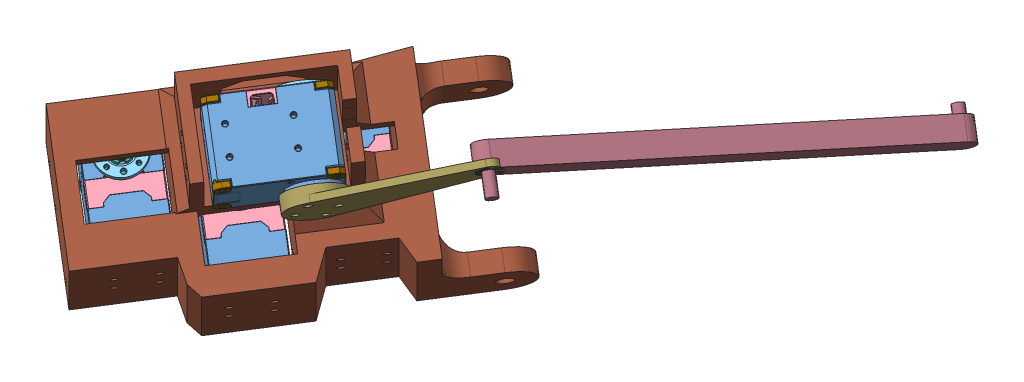
SolidWorks assembly Assemblage Avant bras, configuration Default. Lengths in mm.
Overall size (268.98 138.02 285.22).
110 component instances, 13 part files, 23 mates.
Components (placement in the parent):
- XL-430_new-1: XL-430_new [Default] at (80.3651 -130.963 113.251) x (0.630097 0.085354 -0.771811) z (-0.461076 -0.758631 -0.460313) size (28.5 46.5 40.9)
  - XL-430_new.stp-1: XL-430_new.stp [Default] at origin size (28.5 46.5 40.9)
    - DC11_A01_DUMMY.stp-1: DC11_A01_DUMMY.stp [Default] at origin size (28.5 46.5 37.9)
    - DX124_SCREW-COVER.stp-1: DX124_SCREW-COVER.stp [Default] at (11.75 0 13.7) x (-1 0 0) z (0 1 0) size (3.5 30.65 3.5)
    - B3B-EH.stp-1: B3B-EH.stp [Default] at (10.15 -14.1 -3.8) x (0 -1 0) z (1 0 0) size (10 9.2 3.8)
    - B3B-EH.stp-2: B3B-EH.stp [Default] at (-10.15 -14.1 -3.8) x (0 1 0) z (-1 0 0) size (10 9.2 3.8)
    - DC11_A01_CASE_CVR_DUMMY.stp-1: DC11_A01_CASE_CVR_DUMMY.stp [Default] at origin size (28.3 17.62 8.31)
    - DC11_A01_IDLER_DUMMY.stp-1: DC11_A01_IDLER_DUMMY.stp [Default] at (0 0 -19) x (1 0 0) z (0 1 0) size (20.5 3.5 20.5)
    - DC11_A01_IDLER_CAP_DUMMY.stp-1: DC11_A01_IDLER_CAP_DUMMY.stp [Default] at (0 0 -18.8) x (1 0 0) z (0 -1 0) size (10.1 5.2 10.37)
    - DC11_A01_IDLER_SCREW.stp-1: DC11_A01_IDLER_SCREW.stp [Default] at (0 0 -15.1) x (-1 0 0) z (0 -1 0) size (5 5.01 5)
    - FHS_M2_5X10.stp-1: FHS_M2_5X10.stp [Default] at (11 8 12.95) x (-1 0 0) z (0 1 0) size (5 10.01 5)
    - FHS_M2_5X10.stp-2: FHS_M2_5X10.stp [Default] at (-11 8 12.95) x (-1 0 0) z (0 1 0) size (5 10.01 5)
    - FHS_M2_5X10.stp-3: FHS_M2_5X10.stp [Default] at (-11 -32 12.95) x (-1 0 0) z (0 1 0) size (5 10.01 5)
    - FHS_M2_5X10.stp-4: FHS_M2_5X10.stp [Default] at (11 -32 12.95) x (-1 0 0) z (0 1 0) size (5 10.01 5)
    - FHS_M2_5X10.stp-5: FHS_M2_5X10.stp [Default] at (-11 8 -12.95) x (1 0 0) z (0 1 0) size (5 10.01 5)
    - FHS_M2_5X10.stp-6: FHS_M2_5X10.stp [Default] at (11 8 -12.95) x (1 0 0) z (0 1 0) size (5 10.01 5)
    - FHS_M2_5X10.stp-7: FHS_M2_5X10.stp [Default] at (-11 -32 -12.95) x (1 0 0) z (0 1 0) size (5 10.01 5)
    - FHS_M2_5X10.stp-8: FHS_M2_5X10.stp [Default] at (11 -32 -12.95) x (1 0 0) z (0 1 0) size (5 10.01 5)
    - DC11_A01_SPACER_DUMMY.stp-1: DC11_A01_SPACER_DUMMY.stp [Default] at (11 8 14.2) x (-1 0 0) z (0 0 1) size (6.5 6.5 3.9)
    - DC11_A01_SPACER_DUMMY.stp-2: DC11_A01_SPACER_DUMMY.stp [Default] at (-11 8 14.2) x (0 -1 0) z (0 0 1) size (6.5 6.5 3.9)
    - DC11_A01_SPACER_DUMMY.stp-3: DC11_A01_SPACER_DUMMY.stp [Default] at (-11 -32 14.2) x (-1 0 0) z (0 0 1) size (6.5 6.5 3.9)
    - DC11_A01_SPACER_DUMMY.stp-4: DC11_A01_SPACER_DUMMY.stp [Default] at (11 -32 14.2) x (0 1 0) z (0 0 1) size (6.5 6.5 3.9)
    - DC11_A01_SPACER_DUMMY.stp-5: DC11_A01_SPACER_DUMMY.stp [Default] at (11 8 -14.2) x (0 -1 0) z (0 0 -1) size (6.5 6.5 3.9)
    - DC11_A01_SPACER_DUMMY.stp-6: DC11_A01_SPACER_DUMMY.stp [Default] at (-11 8 -14.2) x (1 0 0) z (0 0 -1) size (6.5 6.5 3.9)
    - DC11_A01_SPACER_DUMMY.stp-7: DC11_A01_SPACER_DUMMY.stp [Default] at (11 -32 -14.2) x (-1 0 0) z (0 0 -1) size (6.5 6.5 3.9)
    - DC11_A01_SPACER_DUMMY.stp-8: DC11_A01_SPACER_DUMMY.stp [Default] at (-11 -32 -14.2) x (0 1 0) z (0 0 -1) size (6.5 6.5 3.9)
- Poulie v2 - Copy-1: Poulie v2 - Copy [Défaut] at (38.8515 -145.3699 130.2405) x (0.27413 -0.615145 0.739222) z (0.461076 0.758631 0.460313) size (28.5 28.5 6.5)
- XL-430_new-2: XL-430_new [Default] at (82.845 -89.2117 140.2604) x (-0.461076 -0.758631 -0.460313) z (0.624809 -0.645906 0.438657) size (28.5 46.5 40.9)
  - XL-430_new.stp-1: XL-430_new.stp [Default] at origin size (28.5 46.5 40.9)
    - DC11_A01_DUMMY.stp-1: DC11_A01_DUMMY.stp [Default] at origin size (28.5 46.5 37.9)
    - DX124_SCREW-COVER.stp-1: DX124_SCREW-COVER.stp [Default] at (11.75 0 13.7) x (-1 0 0) z (0 1 0) size (3.5 30.65 3.5)
    - B3B-EH.stp-1: B3B-EH.stp [Default] at (10.15 -14.1 -3.8) x (0 -1 0) z (1 0 0) size (10 9.2 3.8)
    - B3B-EH.stp-2: B3B-EH.stp [Default] at (-10.15 -14.1 -3.8) x (0 1 0) z (-1 0 0) size (10 9.2 3.8)
    - DC11_A01_CASE_CVR_DUMMY.stp-1: DC11_A01_CASE_CVR_DUMMY.stp [Default] at origin size (28.3 17.62 8.31)
    - DC11_A01_IDLER_DUMMY.stp-1: DC11_A01_IDLER_DUMMY.stp [Default] at (0 0 -19) x (1 0 0) z (0 1 0) size (20.5 3.5 20.5)
    - DC11_A01_IDLER_CAP_DUMMY.stp-1: DC11_A01_IDLER_CAP_DUMMY.stp [Default] at (0 0 -18.8) x (1 0 0) z (0 -1 0) size (10.1 5.2 10.37)
    - DC11_A01_IDLER_SCREW.stp-1: DC11_A01_IDLER_SCREW.stp [Default] at (0 0 -15.1) x (-1 0 0) z (0 -1 0) size (5 5.01 5)
    - FHS_M2_5X10.stp-1: FHS_M2_5X10.stp [Default] at (11 8 12.95) x (-1 0 0) z (0 1 0) size (5 10.01 5)
    - FHS_M2_5X10.stp-2: FHS_M2_5X10.stp [Default] at (-11 8 12.95) x (-1 0 0) z (0 1 0) size (5 10.01 5)
    - FHS_M2_5X10.stp-3: FHS_M2_5X10.stp [Default] at (-11 -32 12.95) x (-1 0 0) z (0 1 0) size (5 10.01 5)
    - FHS_M2_5X10.stp-4: FHS_M2_5X10.stp [Default] at (11 -32 12.95) x (-1 0 0) z (0 1 0) size (5 10.01 5)
    - FHS_M2_5X10.stp-5: FHS_M2_5X10.stp [Default] at (-11 8 -12.95) x (1 0 0) z (0 1 0) size (5 10.01 5)
    - FHS_M2_5X10.stp-6: FHS_M2_5X10.stp [Default] at (11 8 -12.95) x (1 0 0) z (0 1 0) size (5 10.01 5)
    - FHS_M2_5X10.stp-7: FHS_M2_5X10.stp [Default] at (-11 -32 -12.95) x (1 0 0) z (0 1 0) size (5 10.01 5)
    - FHS_M2_5X10.stp-8: FHS_M2_5X10.stp [Default] at (11 -32 -12.95) x (1 0 0) z (0 1 0) size (5 10.01 5)
    - DC11_A01_SPACER_DUMMY.stp-1: DC11_A01_SPACER_DUMMY.stp [Default] at (11 8 14.2) x (-1 0 0) z (0 0 1) size (6.5 6.5 3.9)
    - DC11_A01_SPACER_DUMMY.stp-2: DC11_A01_SPACER_DUMMY.stp [Default] at (-11 8 14.2) x (0 -1 0) z (0 0 1) size (6.5 6.5 3.9)
    - DC11_A01_SPACER_DUMMY.stp-3: DC11_A01_SPACER_DUMMY.stp [Default] at (-11 -32 14.2) x (-1 0 0) z (0 0 1) size (6.5 6.5 3.9)
    - DC11_A01_SPACER_DUMMY.stp-4: DC11_A01_SPACER_DUMMY.stp [Default] at (11 -32 14.2) x (0 1 0) z (0 0 1) size (6.5 6.5 3.9)
    - DC11_A01_SPACER_DUMMY.stp-5: DC11_A01_SPACER_DUMMY.stp [Default] at (11 8 -14.2) x (0 -1 0) z (0 0 -1) size (6.5 6.5 3.9)
    - DC11_A01_SPACER_DUMMY.stp-6: DC11_A01_SPACER_DUMMY.stp [Default] at (-11 8 -14.2) x (1 0 0) z (0 0 -1) size (6.5 6.5 3.9)
    - DC11_A01_SPACER_DUMMY.stp-7: DC11_A01_SPACER_DUMMY.stp [Default] at (11 -32 -14.2) x (-1 0 0) z (0 0 -1) size (6.5 6.5 3.9)
    - DC11_A01_SPACER_DUMMY.stp-8: DC11_A01_SPACER_DUMMY.stp [Default] at (-11 -32 -14.2) x (0 1 0) z (0 0 -1) size (6.5 6.5 3.9)
- FOREARM1 - Copy-1: FOREARM1 - Copy [Default] at (65.464 -108.3061 147.3198) x (-0.624809 0.645906 -0.438657) z (-0.461076 -0.758631 -0.460313) size (80.57 163 95)
- XL-430_new-3: XL-430_new [Default] at (49.1104 -128.4904 140.4824) x (-0.630097 -0.085354 0.771811) z (-0.461076 -0.758631 -0.460313) size (28.5 46.5 40.9)
  - XL-430_new.stp-1: XL-430_new.stp [Default] at origin size (28.5 46.5 40.9)
    - DC11_A01_DUMMY.stp-1: DC11_A01_DUMMY.stp [Default] at origin size (28.5 46.5 37.9)
    - DX124_SCREW-COVER.stp-1: DX124_SCREW-COVER.stp [Default] at (11.75 0 13.7) x (-1 0 0) z (0 1 0) size (3.5 30.65 3.5)
    - B3B-EH.stp-1: B3B-EH.stp [Default] at (10.15 -14.1 -3.8) x (0 -1 0) z (1 0 0) size (10 9.2 3.8)
    - B3B-EH.stp-2: B3B-EH.stp [Default] at (-10.15 -14.1 -3.8) x (0 1 0) z (-1 0 0) size (10 9.2 3.8)
    - DC11_A01_CASE_CVR_DUMMY.stp-1: DC11_A01_CASE_CVR_DUMMY.stp [Default] at origin size (28.3 17.62 8.31)
    - DC11_A01_IDLER_DUMMY.stp-1: DC11_A01_IDLER_DUMMY.stp [Default] at (0 0 -19) x (1 0 0) z (0 1 0) size (20.5 3.5 20.5)
    - DC11_A01_IDLER_CAP_DUMMY.stp-1: DC11_A01_IDLER_CAP_DUMMY.stp [Default] at (0 0 -18.8) x (1 0 0) z (0 -1 0) size (10.1 5.2 10.37)
    - DC11_A01_IDLER_SCREW.stp-1: DC11_A01_IDLER_SCREW.stp [Default] at (0 0 -15.1) x (-1 0 0) z (0 -1 0) size (5 5.01 5)
    - FHS_M2_5X10.stp-1: FHS_M2_5X10.stp [Default] at (11 8 12.95) x (-1 0 0) z (0 1 0) size (5 10.01 5)
    - FHS_M2_5X10.stp-2: FHS_M2_5X10.stp [Default] at (-11 8 12.95) x (-1 0 0) z (0 1 0) size (5 10.01 5)
    - FHS_M2_5X10.stp-3: FHS_M2_5X10.stp [Default] at (-11 -32 12.95) x (-1 0 0) z (0 1 0) size (5 10.01 5)
    - FHS_M2_5X10.stp-4: FHS_M2_5X10.stp [Default] at (11 -32 12.95) x (-1 0 0) z (0 1 0) size (5 10.01 5)
    - FHS_M2_5X10.stp-5: FHS_M2_5X10.stp [Default] at (-11 8 -12.95) x (1 0 0) z (0 1 0) size (5 10.01 5)
    - FHS_M2_5X10.stp-6: FHS_M2_5X10.stp [Default] at (11 8 -12.95) x (1 0 0) z (0 1 0) size (5 10.01 5)
    - FHS_M2_5X10.stp-7: FHS_M2_5X10.stp [Default] at (-11 -32 -12.95) x (1 0 0) z (0 1 0) size (5 10.01 5)
    - FHS_M2_5X10.stp-8: FHS_M2_5X10.stp [Default] at (11 -32 -12.95) x (1 0 0) z (0 1 0) size (5 10.01 5)
    - DC11_A01_SPACER_DUMMY.stp-1: DC11_A01_SPACER_DUMMY.stp [Default] at (11 8 14.2) x (-1 0 0) z (0 0 1) size (6.5 6.5 3.9)
    - DC11_A01_SPACER_DUMMY.stp-2: DC11_A01_SPACER_DUMMY.stp [Default] at (-11 8 14.2) x (0 -1 0) z (0 0 1) size (6.5 6.5 3.9)
    - DC11_A01_SPACER_DUMMY.stp-3: DC11_A01_SPACER_DUMMY.stp [Default] at (-11 -32 14.2) x (-1 0 0) z (0 0 1) size (6.5 6.5 3.9)
    - DC11_A01_SPACER_DUMMY.stp-4: DC11_A01_SPACER_DUMMY.stp [Default] at (11 -32 14.2) x (0 1 0) z (0 0 1) size (6.5 6.5 3.9)
    - DC11_A01_SPACER_DUMMY.stp-5: DC11_A01_SPACER_DUMMY.stp [Default] at (11 8 -14.2) x (0 -1 0) z (0 0 -1) size (6.5 6.5 3.9)
    - DC11_A01_SPACER_DUMMY.stp-6: DC11_A01_SPACER_DUMMY.stp [Default] at (-11 8 -14.2) x (1 0 0) z (0 0 -1) size (6.5 6.5 3.9)
    - DC11_A01_SPACER_DUMMY.stp-7: DC11_A01_SPACER_DUMMY.stp [Default] at (11 -32 -14.2) x (-1 0 0) z (0 0 -1) size (6.5 6.5 3.9)
    - DC11_A01_SPACER_DUMMY.stp-8: DC11_A01_SPACER_DUMMY.stp [Default] at (-11 -32 -14.2) x (0 1 0) z (0 0 -1) size (6.5 6.5 3.9)
- XL-430_new-4: XL-430_new [Default] at (14.396 -121.3361 163.4637) x (-0.630097 -0.085354 0.771811) z (-0.461076 -0.758631 -0.460313) size (28.5 46.5 40.9)
  - XL-430_new.stp-1: XL-430_new.stp [Default] at origin size (28.5 46.5 40.9)
    - DC11_A01_DUMMY.stp-1: DC11_A01_DUMMY.stp [Default] at origin size (28.5 46.5 37.9)
    - DX124_SCREW-COVER.stp-1: DX124_SCREW-COVER.stp [Default] at (11.75 0 13.7) x (-1 0 0) z (0 1 0) size (3.5 30.65 3.5)
    - B3B-EH.stp-1: B3B-EH.stp [Default] at (10.15 -14.1 -3.8) x (0 -1 0) z (1 0 0) size (10 9.2 3.8)
    - B3B-EH.stp-2: B3B-EH.stp [Default] at (-10.15 -14.1 -3.8) x (0 1 0) z (-1 0 0) size (10 9.2 3.8)
    - DC11_A01_CASE_CVR_DUMMY.stp-1: DC11_A01_CASE_CVR_DUMMY.stp [Default] at origin size (28.3 17.62 8.31)
    - DC11_A01_IDLER_DUMMY.stp-1: DC11_A01_IDLER_DUMMY.stp [Default] at (0 0 -19) x (1 0 0) z (0 1 0) size (20.5 3.5 20.5)
    - DC11_A01_IDLER_CAP_DUMMY.stp-1: DC11_A01_IDLER_CAP_DUMMY.stp [Default] at (0 0 -18.8) x (1 0 0) z (0 -1 0) size (10.1 5.2 10.37)
    - DC11_A01_IDLER_SCREW.stp-1: DC11_A01_IDLER_SCREW.stp [Default] at (0 0 -15.1) x (-1 0 0) z (0 -1 0) size (5 5.01 5)
    - FHS_M2_5X10.stp-1: FHS_M2_5X10.stp [Default] at (11 8 12.95) x (-1 0 0) z (0 1 0) size (5 10.01 5)
    - FHS_M2_5X10.stp-2: FHS_M2_5X10.stp [Default] at (-11 8 12.95) x (-1 0 0) z (0 1 0) size (5 10.01 5)
    - FHS_M2_5X10.stp-3: FHS_M2_5X10.stp [Default] at (-11 -32 12.95) x (-1 0 0) z (0 1 0) size (5 10.01 5)
    - FHS_M2_5X10.stp-4: FHS_M2_5X10.stp [Default] at (11 -32 12.95) x (-1 0 0) z (0 1 0) size (5 10.01 5)
    - FHS_M2_5X10.stp-5: FHS_M2_5X10.stp [Default] at (-11 8 -12.95) x (1 0 0) z (0 1 0) size (5 10.01 5)
    - FHS_M2_5X10.stp-6: FHS_M2_5X10.stp [Default] at (11 8 -12.95) x (1 0 0) z (0 1 0) size (5 10.01 5)
    - FHS_M2_5X10.stp-7: FHS_M2_5X10.stp [Default] at (-11 -32 -12.95) x (1 0 0) z (0 1 0) size (5 10.01 5)
    - FHS_M2_5X10.stp-8: FHS_M2_5X10.stp [Default] at (11 -32 -12.95) x (1 0 0) z (0 1 0) size (5 10.01 5)
    - DC11_A01_SPACER_DUMMY.stp-1: DC11_A01_SPACER_DUMMY.stp [Default] at (11 8 14.2) x (-1 0 0) z (0 0 1) size (6.5 6.5 3.9)
    - DC11_A01_SPACER_DUMMY.stp-2: DC11_A01_SPACER_DUMMY.stp [Default] at (-11 8 14.2) x (0 -1 0) z (0 0 1) size (6.5 6.5 3.9)
    - DC11_A01_SPACER_DUMMY.stp-3: DC11_A01_SPACER_DUMMY.stp [Default] at (-11 -32 14.2) x (-1 0 0) z (0 0 1) size (6.5 6.5 3.9)
    - DC11_A01_SPACER_DUMMY.stp-4: DC11_A01_SPACER_DUMMY.stp [Default] at (11 -32 14.2) x (0 1 0) z (0 0 1) size (6.5 6.5 3.9)
    - DC11_A01_SPACER_DUMMY.stp-5: DC11_A01_SPACER_DUMMY.stp [Default] at (11 8 -14.2) x (0 -1 0) z (0 0 -1) size (6.5 6.5 3.9)
    - DC11_A01_SPACER_DUMMY.stp-6: DC11_A01_SPACER_DUMMY.stp [Default] at (-11 8 -14.2) x (1 0 0) z (0 0 -1) size (6.5 6.5 3.9)
    - DC11_A01_SPACER_DUMMY.stp-7: DC11_A01_SPACER_DUMMY.stp [Default] at (11 -32 -14.2) x (-1 0 0) z (0 0 -1) size (6.5 6.5 3.9)
    - DC11_A01_SPACER_DUMMY.stp-8: DC11_A01_SPACER_DUMMY.stp [Default] at (-11 -32 -14.2) x (0 1 0) z (0 0 -1) size (6.5 6.5 3.9)
- Poulie v2 - Copy-2: Poulie v2 - Copy [Défaut] at (70.1062 -147.8425 103.009) x (0.27413 -0.615145 0.739222) z (0.461076 0.758631 0.460313) size (28.5 28.5 6.5)
- Poulie v2 - Copy-3: Poulie v2 - Copy [Défaut] at (4.137 -138.2157 153.2217) x (0.27413 -0.615145 0.739222) z (0.461076 0.758631 0.460313) size (28.5 28.5 6.5)
- Mécanisme poignet 1-1: Mécanisme poignet 1 [Défaut] at (96.6845 -103.5186 149.9767) x (0.19189 0.671621 0.715614) z (-0.624809 0.645906 -0.438657) size (25 82.55 8.57)
- Mécanisme poignet 2-1: Mécanisme poignet 2 [Défaut] at (156.98 -84.0215 88.5281) x (0.469024 -0.138658 -0.872233) z (0.624809 -0.645906 0.438657) size (184 10 25)
Mates (geometry in assembly coordinates):
- Distance2: distance = 1.5 mm anti-aligned: plane of XL-430_new-1/XL-430_new.stp-1/DC11_A01_DUMMY.stp-1 through (87.2746 -150.0805 100.9058) normal (0.624809 -0.645906 0.438657); plane of FOREARM1 - Copy-1 through (107.477 -122.6813 115.8941) normal (-0.624809 0.645906 -0.438657)
- Coïncidente10: coincident anti-aligned: plane of XL-430_new-1/XL-430_new.stp-1/DC11_A01_IDLER_CAP_DUMMY.stp-1 through (89.5866 -115.7904 122.4572) normal (0.461076 0.758631 0.460313); plane of FOREARM1 - Copy-1 through (62.6976 -112.8579 144.5579) normal (-0.461076 -0.758631 -0.460313)
- Distance1: distance = 1.5 mm anti-aligned: plane of XL-430_new-1/XL-430_new.stp-1/DC11_A01_DUMMY.stp-1 through (60.7308 -121.167 79.842) normal (0.630097 0.085354 -0.771811); plane of FOREARM1 - Copy-1 through (107.477 -122.6813 115.8941) normal (-0.630097 -0.085354 0.771811)
- Coïncidente12: coincident anti-aligned: plane of XL-430_new-2/XL-430_new.stp-1/DC11_A01_IDLER_CAP_DUMMY.stp-1 through (70.3488 -76.2936 131.4873) normal (-0.624809 0.645906 -0.438657); plane of FOREARM1 - Copy-1 through (50.1125 -92.4362 136.542) normal (0.624809 -0.645906 0.438657)
- Coïncidente14: coincident anti-aligned: plane of XL-430_new-2/XL-430_new.stp-1/DC11_A01_DUMMY.stp-1 through (65.9457 -113.8406 166.8208) normal (-0.461076 -0.758631 -0.460313); plane of FOREARM1 - Copy-1 through (98.9941 -113.7471 133.5636) normal (0.461076 0.758631 0.460313)
- Coïncidente15: coincident anti-aligned: plane of FOREARM1 - Copy-1 through (62.6976 -112.8579 144.5579) normal (-0.461076 -0.758631 -0.460313); plane of XL-430_new-3/XL-430_new.stp-1/DC11_A01_IDLER_CAP_DUMMY.stp-1 through (58.3319 -113.3178 149.6887) normal (0.461076 0.758631 0.460313)
- Distance5: distance = 1.5 mm anti-aligned: plane of FOREARM1 - Copy-1 through (60.9198 -103.6528 131.168) normal (0.624809 -0.645906 0.438657); plane of XL-430_new-3/XL-430_new.stp-1/DC11_A01_DUMMY.stp-1 through (26.5243 -135.1663 137.1769) normal (-0.624809 0.645906 -0.438657)
- Distance4: distance = 1.5 mm anti-aligned: plane of FOREARM1 - Copy-1 through (71.9945 -139.045 178.404) normal (0.630097 0.085354 -0.771811); plane of XL-430_new-3/XL-430_new.stp-1/DC11_A01_DUMMY.stp-1 through (53.0682 -164.0798 158.2407) normal (-0.630097 -0.085354 0.771811)
- Coïncidente18: coincident anti-aligned: plane of FOREARM1 - Copy-1 through (62.6976 -112.8579 144.5579) normal (-0.461076 -0.758631 -0.460313); plane of XL-430_new-4/XL-430_new.stp-1/DC11_A01_IDLER_CAP_DUMMY.stp-1 through (23.6175 -106.1635 172.6699) normal (0.461076 0.758631 0.460313)
- Distance7: distance = 1.5 mm anti-aligned: plane of FOREARM1 - Copy-1 through (25.8903 -96.5412 154.5351) normal (0.624809 -0.645906 0.438657); plane of XL-430_new-4/XL-430_new.stp-1/DC11_A01_DUMMY.stp-1 through (-8.1901 -128.012 160.1581) normal (-0.624809 0.645906 -0.438657)
- Distance6: distance = 2 mm anti-aligned: plane of FOREARM1 - Copy-1 through (36.965 -131.9335 201.7711) normal (0.630097 0.085354 -0.771811); plane of XL-430_new-4/XL-430_new.stp-1/DC11_A01_DUMMY.stp-1 through (18.3537 -156.9255 181.222) normal (-0.630097 -0.085354 0.771811)
- Coaxiale1: concentric anti-aligned: cylinder of Poulie v2 - Copy-1 through (37.353 -147.8355 128.7444) axis (0.461076 0.758631 0.460313) radius 4; cylinder of XL-430_new-3/XL-430_new.stp-1/DC11_A01_DUMMY.stp-1 through (40.35 -142.9044 131.7365) axis (-0.461076 -0.758631 -0.460313) radius 4
- Coaxiale2: concentric anti-aligned: circle of XL-430_new-1/XL-430_new.stp-1/DC11_A01_DUMMY.stp-1; circle of Poulie v2 - Copy-2
- Coïncidente19: coincident anti-aligned: plane of XL-430_new-1/XL-430_new.stp-1/DC11_A01_DUMMY.stp-1 through (71.6047 -145.377 104.505) normal (-0.461076 -0.758631 -0.460313); plane of Poulie v2 - Copy-2 through (71.6047 -145.377 104.505) normal (0.461076 0.758631 0.460313)
- Coïncidente20: coincident anti-aligned: plane of Poulie v2 - Copy-1 through (40.35 -142.9044 131.7365) normal (0.461076 0.758631 0.460313); plane of XL-430_new-3/XL-430_new.stp-1/DC11_A01_DUMMY.stp-1 through (40.35 -142.9044 131.7365) normal (-0.461076 -0.758631 -0.460313)
- Coaxiale3: concentric anti-aligned: circle of XL-430_new-4/XL-430_new.stp-1/DC11_A01_DUMMY.stp-1; circle of Poulie v2 - Copy-3
- Coïncidente21: coincident anti-aligned: plane of XL-430_new-4/XL-430_new.stp-1/DC11_A01_DUMMY.stp-1 through (5.6355 -135.7501 154.7177) normal (-0.461076 -0.758631 -0.460313); plane of Poulie v2 - Copy-3 through (5.6355 -135.7501 154.7177) normal (0.461076 0.758631 0.460313)
- Distance8: distance = 3 mm anti-aligned: plane of XL-430_new-2/XL-430_new.stp-1/DC11_A01_DUMMY.stp-1 through (76.904 -93.9076 180.5628) normal (-0.630097 -0.085354 0.771811); plane of FOREARM1 - Copy-1 through (102.6676 -116.5749 202.9761) normal (0.630097 0.085354 -0.771811)
- Coaxiale4: concentric anti-aligned: circle of XL-430_new-2/XL-430_new.stp-1/DC11_A01_DUMMY.stp-1; circle of Poulie v2 - Copy-4
- Coïncidente24: coincident anti-aligned: plane of XL-430_new-2/XL-430_new.stp-1/DC11_A01_DUMMY.stp-1 through (94.7164 -101.484 148.5949) normal (0.624809 -0.645906 0.438657); plane of Poulie v2 - Copy-4 through (11.673 -26.9487 182.3704) normal (1 0 0)
- Coaxiale5: concentric anti-aligned: circle of XL-430_new-2/XL-430_new.stp-1/DC11_A01_DUMMY.stp-1; circle of Mécanisme poignet 1-1
- Coïncidente25: coincident anti-aligned: plane of XL-430_new-2/XL-430_new.stp-1/DC11_A01_DUMMY.stp-1 through (95.9035 -102.7112 149.4284) normal (0.624809 -0.645906 0.438657); plane of Mécanisme poignet 1-1 through (95.9035 -102.7112 149.4284) normal (-0.624809 0.645906 -0.438657)
- Coïncidente26: coincident anti-aligned: circle of Mécanisme poignet 1-1; circle of Mécanisme poignet 2-1
